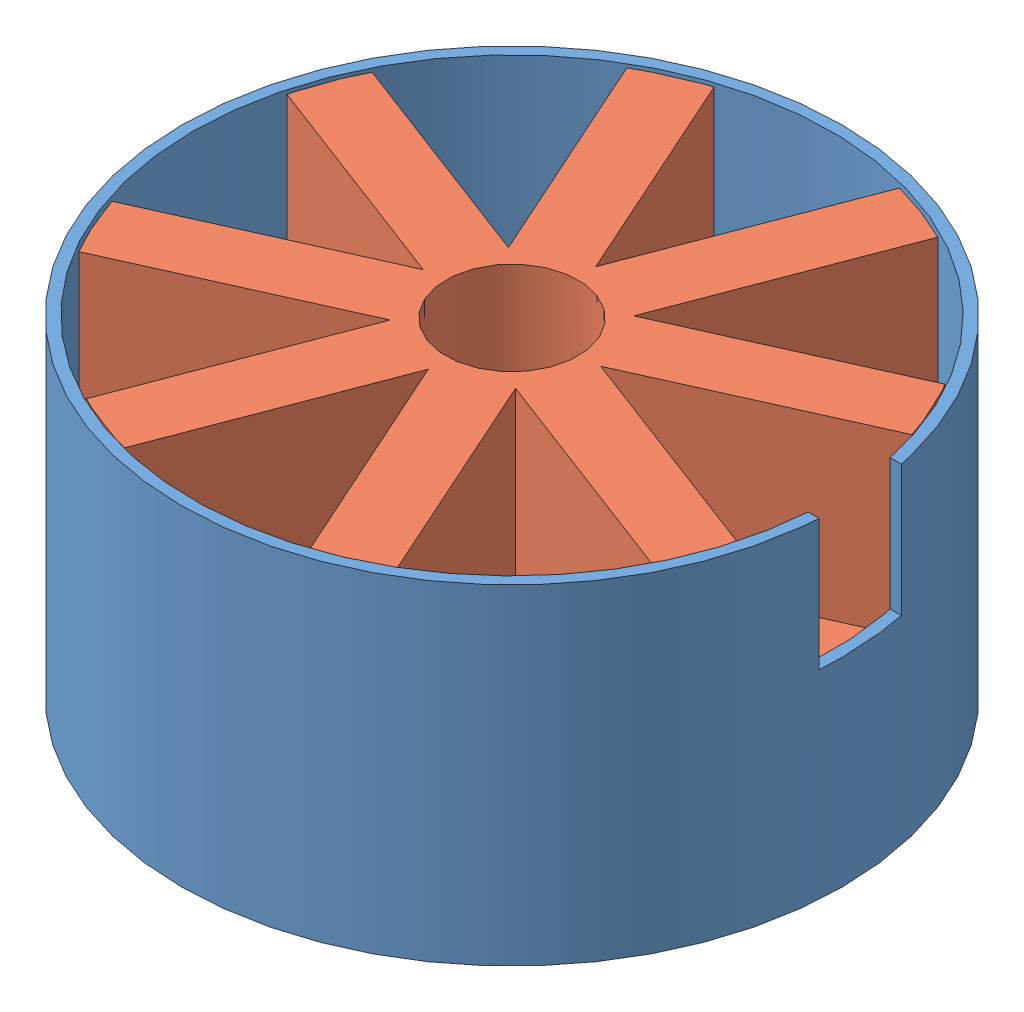
SolidWorks assembly dispenser, configuration Default. Lengths in mm.
Overall size (371.58 150 371.58).
3 component instances, 3 part files, 4 mates.
Components (placement in the parent):
- medicine dispenser shwll-1: medicine dispenser shwll [Default] at (113.8952 122.365 276.5413) x (1 0 0) z (0 1 0) size (300 300 150)
- medicine dispenser roatating part-1: medicine dispenser roatating part [Default] at (113.8952 177.365 276.5413) x (0.934657 0 0.35555) z (-0.35555 0 0.934657) size (288 94 288)
- medicine dispenser lid-1: medicine dispenser lid [Default] at (113.8952 272.365 276.5413) x (0.085182 0 0.996365) z (-0.996365 0 0.085182) size (300 10 300) (hidden)
Mates (geometry in assembly coordinates):
- Distance1: distance = 50 mm anti-aligned: plane of medicine dispenser roatating part-1 through (113.8952 177.365 276.5413) normal (0 -1 0); plane of medicine dispenser shwll-1 through (113.8952 127.365 276.5413) normal (0 1 0)
- Concentric1: concentric aligned: circle of medicine dispenser shwll-1; circle of medicine dispenser roatating part-1
- Coincident2: coincident anti-aligned: plane of medicine dispenser shwll-1 through (113.8952 272.365 276.5413) normal (0 1 0); plane of medicine dispenser lid-1 through (113.8952 272.365 276.5413) normal (0 -1 0)
- Coincident3: coincident aligned: circle of medicine dispenser shwll-1; circle of medicine dispenser lid-1
